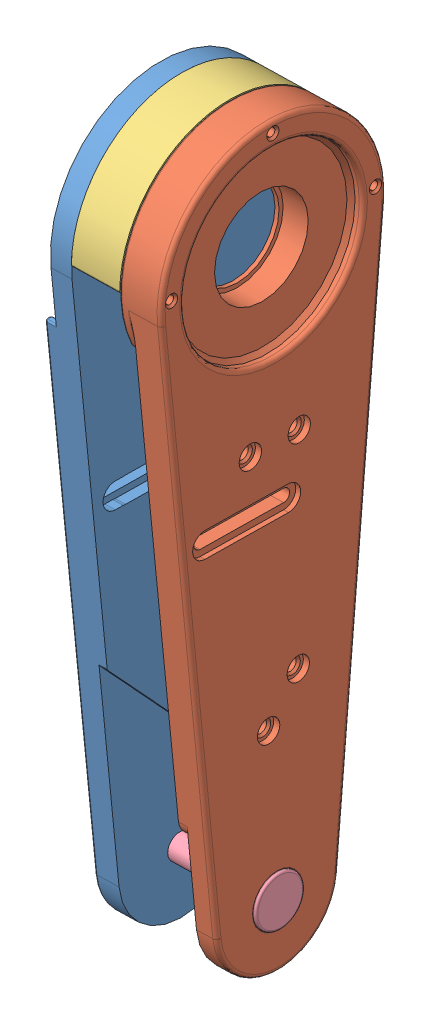
SolidWorks assembly RF_THIGH_LINK, configuration 默认. Lengths in mm.
Overall size (55.45 186.13 95.03).
4 component instances, 4 part files, 8 mates.
Components (placement in the parent):
- 大足-1: 大足 [默认] at (90.6399 -0.0722 -119.9) x (-0.00031 0.014225 0.999899) z (-0.999763 -0.021754 0) size (55.2 177.6 19.75)
- 大足2-1: 大足2 [默认] at (105.3864 0.2487 -119.9) x (0.00031 -0.014225 -0.999899) z (0.999763 0.021754 0) size (55.62 177.6 10.15)
- 支撑半环-1: 支撑半环 [默认] at (93.5392 -0.0091 -119.9) x (0.000311 -0.014305 -0.999898) z (0.021752 -0.999661 0.014309) size (55.19 11.85 27.6)
- 字母钉-1: 字母钉 [默认] at (103.774 -134.8047 -117.9792) x (0.021754 -0.999755 0.004183) z (0.000091 -0.004182 -0.999991) size (12 30.6 12)
Mates (geometry in assembly coordinates):
- 同心478: concentric anti-aligned: cylinder of 大足2-1 through (115.534 0.4695 -119.9) axis (-0.999763 -0.021754 0) radius 27.6; cylinder of 大足-1 through (9.5945 -1.8357 -119.9) axis (0.999763 0.021754 0) radius 27.6
- 同心479: concentric aligned: circle of 大足2-1; cylinder of 大足-1 through (82.479 -135.268 -117.9792) axis (0.999763 0.021754 0) radius 3.47
- 同心480: concentric anti-aligned: cylinder of 大足-1 through (9.5945 -1.8357 -119.9) axis (0.999763 0.021754 0) radius 27.6; cylinder of 支撑半环-1 through (105.3864 0.2487 -119.9) axis (-0.999763 -0.021754 0) radius 27.6
- 同心481: concentric aligned: cylinder of 大足-1 through (85.5514 2.2059 -94.9139) axis (0.999763 0.021754 0) radius 0.81; cylinder of 支撑半环-1 through (93.4873 2.3786 -94.9139) axis (0.999763 0.021754 0) radius 1
- 重合191: coincident anti-aligned: plane of 大足-1 through (93.5392 -0.0091 -119.9) normal (0.999763 0.021754 0); plane of 支撑半环-1 through (93.5392 -0.0091 -119.9) normal (-0.999763 -0.021754 0)
- 重合192: coincident anti-aligned: plane of 大足2-1 through (105.3864 0.2487 -119.9) normal (-0.999763 -0.021754 0); plane of 支撑半环-1 through (105.3864 0.2487 -119.9) normal (0.999763 0.021754 0)
- 同心609: concentric aligned: cylinder of 大足-1 through (82.479 -135.268 -117.9792) axis (0.999763 0.021754 0) radius 3.47; cylinder of 字母钉-1 through (89.4774 -135.1158 -117.9792) axis (0.999763 0.021754 0) radius 3
- 重合343: coincident anti-aligned: plane of 大足-1 through (89.4774 -135.1158 -117.9792) normal (-0.999763 -0.021754 0); plane of 字母钉-1 through (89.4774 -135.1158 -117.9792) normal (0.999763 0.021754 0)
